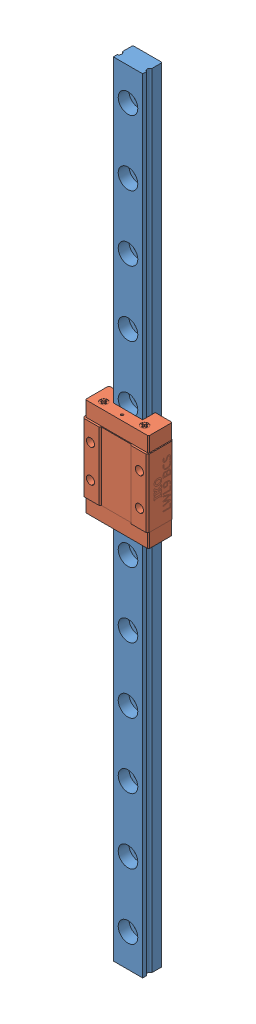
SolidWorks assembly Linear guide assembly, configuration Default. Lengths in mm.
Overall size (20 240 10).
2 component instances, 2 part files, 2 mates.
Components (placement in the parent):
- IKO LWL9 BCS linear guideway rail 240mm.step-1: IKO LWL9 BCS linear guideway rail 240mm.step [Default] at (-31.0497 21.9181 -1.5064) size (9 240 6)
- IKO LWL9 BCS linear guideway block.step-1: IKO LWL9 BCS linear guideway block.step [Default] at (-31.0497 35.0683 -1.5064) size (20 30 8)
Mates (geometry in assembly coordinates):
- Coincident1: coincident anti-aligned: plane of IKO LWL9 BCS linear guideway rail 240mm.step-1 through (-28.7997 -98.0819 4.4936) normal (0 0 1); plane of IKO LWL9 BCS linear guideway block.step-1 through (-28.7997 20.0683 4.4936) normal (0 0 -1)
- Coincident2: coincident anti-aligned: plane of IKO LWL9 BCS linear guideway rail 240mm.step-1 through (-35.5497 -98.0819 0.2186) normal (-1 0 0); plane of IKO LWL9 BCS linear guideway block.step-1 through (-35.5497 20.0683 2.5686) normal (1 0 0)
